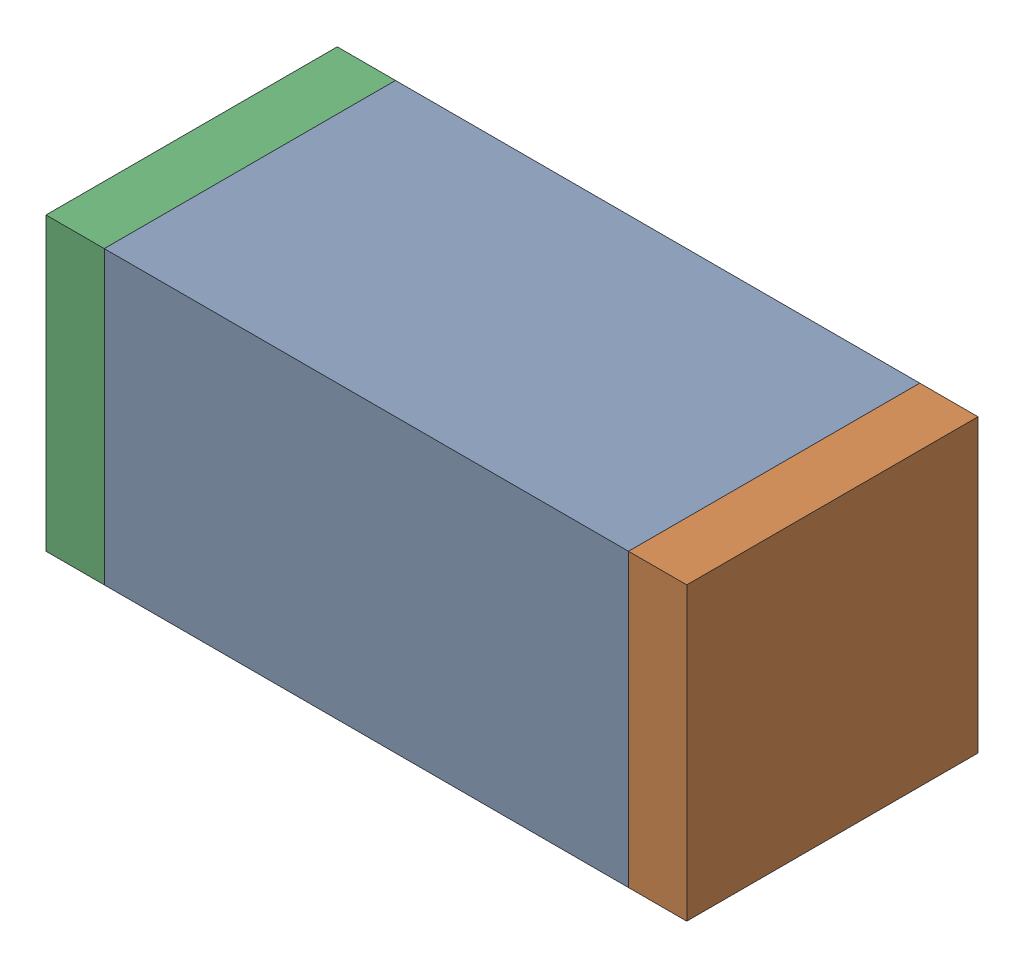
SolidWorks assembly C96, configuration Default. Lengths in mm.
Overall size (1.1 0.5 0.5).
6 component instances, 2 part files, 0 mates.
Components (placement in the parent):
- 836749680-1: 836749680 [Default] at (127.95 68.8 0) size (0.9 0.5 0.5)
  - Extruded_4-1: Extruded_4 [Default] at origin size (0.9 0.5 0.5)
- 810156080-1: 810156080 [Default] at (128.45 68.8 0) size (0.1 0.5 0.5)
  - Extruded_5-1: Extruded_5 [Default] at origin size (0.1 0.5 0.5)
- 810156080-2: 810156080 [Default] at (127.45 68.8 0) size (0.1 0.5 0.5)
  - Extruded_5-1: Extruded_5 [Default] at origin size (0.1 0.5 0.5)
